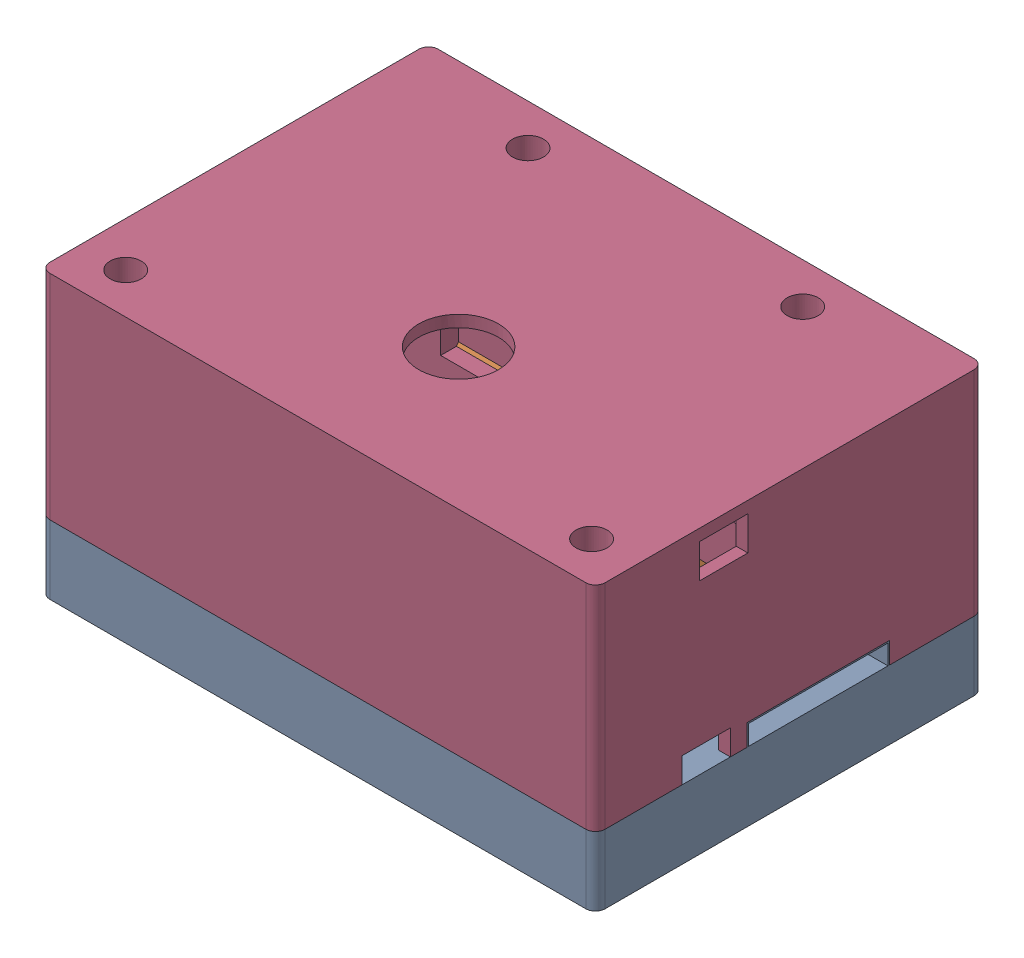
SolidWorks assembly Mont1, configuration Valor predeterminado. Lengths in mm.
Overall size (57.3 29.24 40.6).
4 component instances, 4 part files, 7 mates.
Components (placement in the parent):
- modulo-1: modulo [Valor predeterminado] at (-73.9206 -8.7691 20) size (57.2 14.1 40.6)
- bateria-1: bateria [Valor predeterminado] at (-18.6942 11.0809 -5.25) x (0 0.18272 -0.983165) z (0 0.983165 0.18272) size (16.1 35 16.1)
- placa bateria-1: placa bateria [Valor predeterminado] at (-54.7206 19.1309 -11.85) x (0 0 1) z (1 0 0) size (23.7 4.1 19.3)
- case-3: case [Valor predeterminado] at (-16.7206 -1.6691 -20) x (-1 0 0) z (0 0 -1) size (57.2 22 40)
Mates (geometry in assembly coordinates):
- Coincidente3: coincident aligned: plane of modulo-1 through (-73.9206 -1.6691 20) normal (0 0 1); plane of case-3 through (-16.7206 20.3309 20) normal (0 0 1)
- Coincidente4: coincident aligned: plane of modulo-1 through (-73.9206 -1.6691 20) normal (-1 0 0); plane of case-3 through (-73.9206 20.3309 -20) normal (-1 0 0)
- Coincidente5: coincident anti-aligned: plane of modulo-1 through (-73.9206 -1.6691 20) normal (0 1 0); plane of case-3 through (-16.7206 -1.6691 -20) normal (0 -1 0)
- Concêntrico1: concentric aligned: cylinder of bateria-1 through (-53.6942 11.0809 -5.25) axis (1 0 0) radius 8.05; cylinder of case-3 through (-53.7206 11.0809 -5.25) axis (1 0 0) radius 8.05
- Coincidente6: coincident anti-aligned: plane of placa bateria-1 through (-54.7206 18.0309 11.85) normal (0 0 1); plane of case-3 through (-16.7206 16.1309 11.85) normal (0 0 -1)
- Coincidente7: coincident anti-aligned: plane of placa bateria-1 through (-54.7206 18.0309 -11.85) normal (1 0 0); plane of case-3 through (-54.7206 16.1309 -20) normal (-1 0 0)
- Coincidente8: coincident anti-aligned: plane of placa bateria-1 through (-54.7206 19.1309 -11.85) normal (0 1 0); plane of case-3 through (-16.7206 19.1309 -20) normal (0 -1 0)
